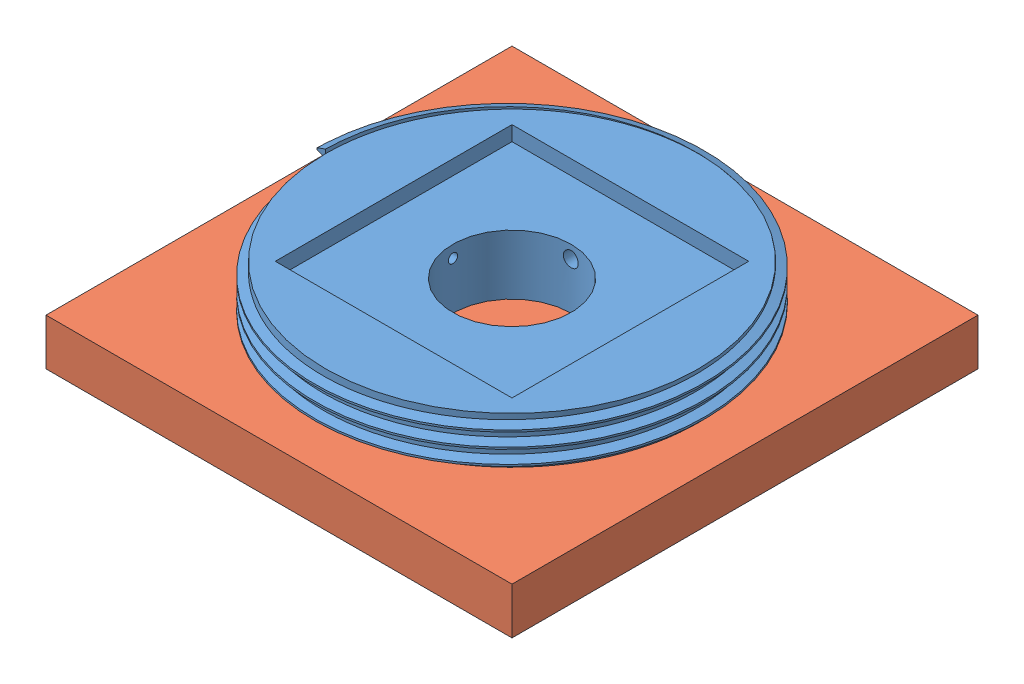
SolidWorks assembly ASIteration5, configuration Default. Lengths in mm.
Overall size (50 10.46 50).
2 component instances, 2 part files, 2 mates.
Components (placement in the parent):
- innerCircle-1: innerCircle [Default] at (0 2.7806 0) x (1 0 0.000011) z (-0.000011 0 1) size (41.85 8.86 41.83)
- Bottom-1: Bottom [Default] at (0 2.7806 0) x (0.000011 0 -1) z (0 1 0) size (50 50 10.46)
Mates (geometry in assembly coordinates):
- Coincident2: coincident anti-aligned: line of innerCircle-1 through (8 0 10.7806) axis (0 0 -1); line of Bottom-1 through (10 0 0.7806) axis (0 0 1)
- Screw1: screw = 0.625 aligned: cylinder of innerCircle-1 through (0 10.7806 0) axis (0 -1 0) radius 20; cylinder of Bottom-1 through (0 10.7806 0) axis (0 -1 0) radius 20
